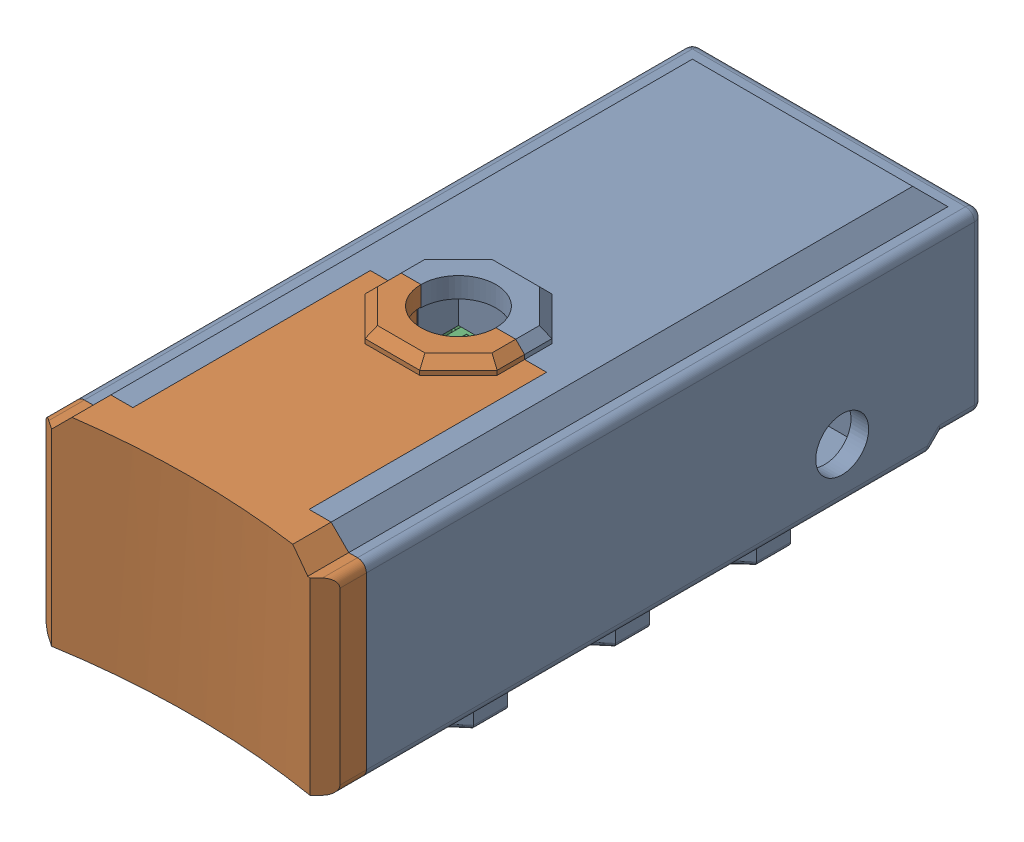
SolidWorks assembly ESP2, configuration Default. Lengths in mm.
Overall size (33 29.85 74.72).
4 component instances, 4 part files, 9 mates.
Components (placement in the parent):
- Camcase_body_V2-1: Camcase_body_V2 [Default] at (-11.4693 -1.558 -27.4589) size (33 29.85 70)
- COLOUSENSOR_PCB_REFERENCE-1: COLOUSENSOR_PCB_REFERENCE [Default] at (-20.2193 3.192 25.9661) x (1 0 0) z (0 1 0) (suppressed, hidden)
- Camcase_lid_V2-1: Camcase_lid_V2 [Default] at (-11.4693 -2.233 45.5411) x (-1 0 0) z (0 0 -1) size (33 24.85 31.67)
- ESP32-cam-withpins-1: ESP32-cam-withpins [Default] at (-11.3693 -1.908 13.5411) x (-1 0 0) z (0 1 0) size (27 40 19.1)
Mates (geometry in assembly coordinates):
- Coincident4: coincident aligned: plane of Camcase_V2_lid-1 through (-27.9693 -2.233 42.5411) normal (-1 0 0); plane of Camcase_body_V2-1 through (-27.9693 8.442 42.5411) normal (-1 0 0)
- Coincident5: coincident anti-aligned: plane of Camcase_body_V2-1 through (-7.4693 6.442 15.5911) normal (0 0 1); plane of Camcase_V2_lid-1 through (-11.4693 -2.233 15.5911) normal (0 0 -1)
- Coincident6: coincident: plane of Camcase_body_V2-1 through (-24.2193 -1.908 -27.4589) normal (0 1 0); plane of ESP32-cam-withpins-1 through (-22.8693 -1.908 -4.4589) normal (0 -1 0)
- Coincident7: coincident anti-aligned: plane of Camcase_body_V2-1 through (-11.4693 -1.558 -6.4589) normal (0 0 1); plane of ESP32-cam-withpins-1 through (0.1307 -0.408 -6.4589) normal (0 0 -1)
- Coincident8: coincident anti-aligned: plane of Camcase_body_V2-1 through (-7.4693 6.442 15.5911) normal (0 0 1); plane of Camcase_V2_lid-1 through (-11.4693 -2.233 15.3911) normal (0 0 -1)
- Coincident9: coincident aligned: plane of Camcase_body_V2-1 through (-11.4693 10.442 -27.4589) normal (0 1 0); plane of Camcase_V2_lid-1 through (-11.4693 10.442 42.3411) normal (0 1 0)
- Coincident10: coincident anti-aligned: plane of Camcase_body_V2-1 through (-6.8693 9.642 10.9911) normal (0 0 1); plane of ESP32-cam-withpins-1 through (-6.8693 9.2265 10.9911) normal (0 0 -1)
- Coincident11: coincident anti-aligned: plane of Camcase_V2_lid-1 through (-6.8693 9.642 19.9911) normal (0 0 -1); plane of ESP32-cam-withpins-1 through (-6.8693 9.2265 19.9911) normal (0 0 1)
- Coincident12: coincident anti-aligned: plane of Camcase_V2_lid-1 through (-6.8693 9.642 15.6068) normal (-1 0 0); plane of ESP32-cam-withpins-1 through (-6.8693 9.2265 10.9911) normal (1 0 0)
